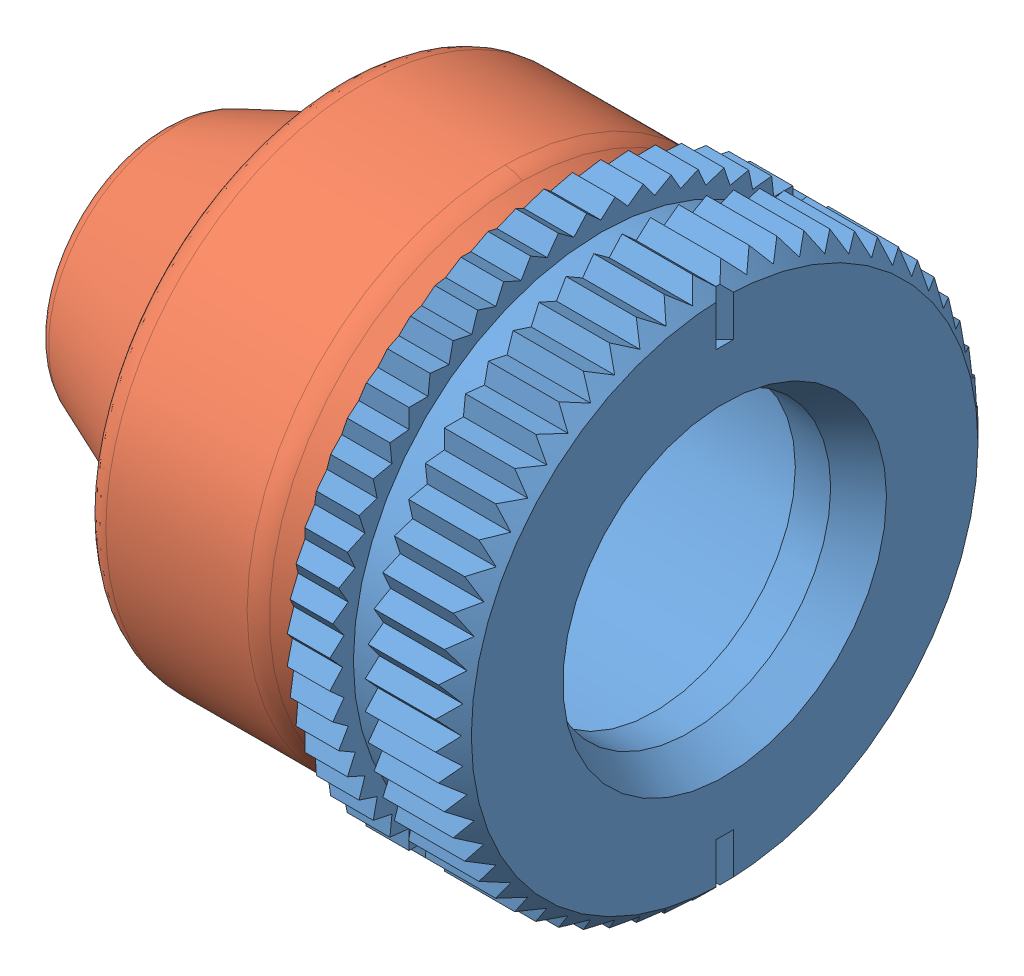
SolidWorks assembly Southco-D8-336-100-300, configuration Default. Lengths in mm.
Overall size (15.99 15.33 15.33).
3 component instances, 3 part files, 0 mates.
Components (placement in the parent):
- SW3dPS-D8-336-100-300_D8-336-101-300-1: SW3dPS-D8-336-100-300_D8-336-101-300 [Default] at (10.75 6.7 -6.7039) size (10.5 15.33 15.33)
- SW3dPS-D8-336-100-300_D8-336-114-190-ASSY-1: SW3dPS-D8-336-100-300_D8-336-114-190-ASSY [Default] at (0.2587 6.7 -6.7039) size (10.93 14.55 14.56)
- SW3dPS-D8-336-100-300_D8-336-113-190-1: SW3dPS-D8-336-100-300_D8-336-113-190 [Default] at (1.2587 6.7 -6.7039) size (2.5 13.1 11)
